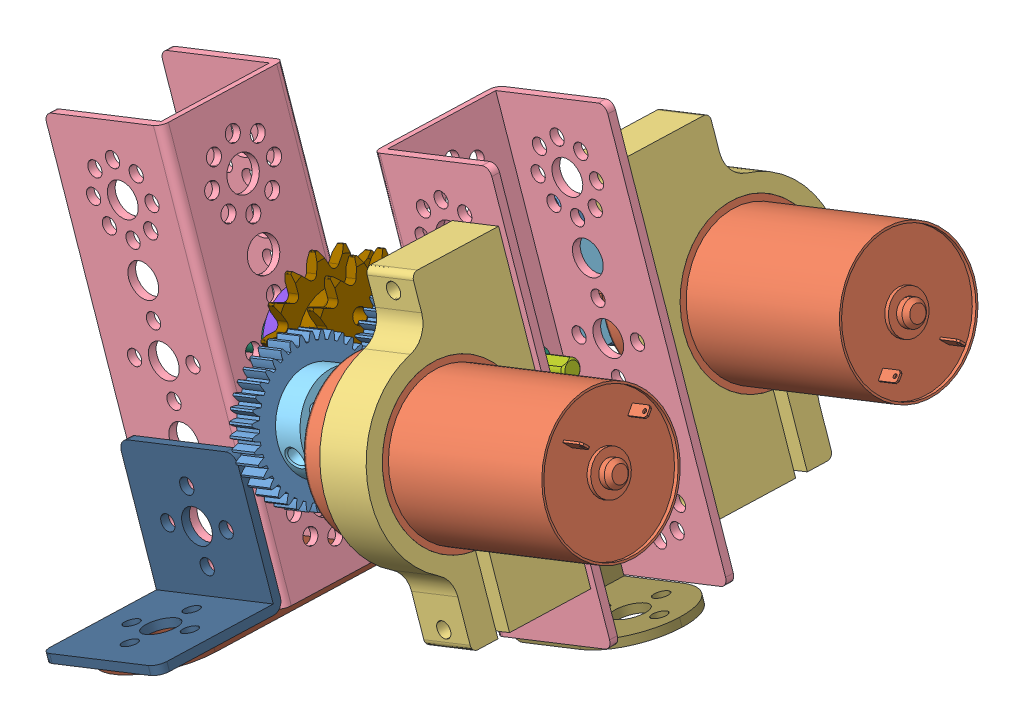
SolidWorks assembly Base Gearbox, configuration Default. Lengths in mm.
Overall size (179.16 136.45 124.21).
22 component instances, 12 part files, 56 mates.
Components (placement in the parent):
- Gear Metric 40T-5: Gear Metric 40T [PreviewCfg] at (251.3927 353.961 -2.865) x (0.93253 0.360914 -0.011317) z (-0.302942 0.799028 0.519404) size (6.2 33.53 33.53)
- Gear Metric 40T-6: Gear Metric 40T [PreviewCfg] at (251.3714 356.0218 61.1018) x (0.93253 0.360914 -0.011317) z (0.242761 -0.649832 -0.720268) size (6.2 33.53 33.53)
- DC gearhead motor-1: DC gearhead motor [Default] at (298.6742 372.0501 -9.9354) x (0.361091 -0.932043 0.030148) z (0.000333 -0.0322 -0.999481) size (37 98.8 37)
- DC gearhead motor-2: DC gearhead motor [Default] at (298.6485 374.5295 67.0247) x (-0.361091 0.932043 -0.030148) z (-0.000333 0.0322 0.999481) size (37 98.8 37)
- Tetrix Motor Mount-5: Tetrix Motor Mount [Default] at (291.2273 357.2311 -9.3463) x (-0.361091 0.932043 -0.030148) z (-0.93253 -0.360914 0.011317) size (72 44.98 12.7)
- Tetrix Motor Mount-6: Tetrix Motor Mount [Default] at (302.2979 363.9977 67.2511) x (-0.361091 0.932043 -0.030148) z (0.93253 0.360914 -0.011317) size (72 44.98 12.7)
- Tetrix 96mm-1: Tetrix 96mm [Default] at (302.6119 323.3726 30.1542) x (-0.000333 0.0322 0.999481) z (0.361091 -0.932043 0.030148) size (32 32 96)
- Hub motor shaft-5: Hub motor shaft [Default] at (257.1744 356.1987 -2.9351) x (-0.196503 0.480932 -0.854454) z (-0.93253 -0.360914 0.011317) size (22 22 9.5)
- Hub motor shaft-6: Hub motor shaft [Default] at (257.1531 358.2595 61.0317) x (0.267309 -0.668924 0.693604) z (-0.93253 -0.360914 0.011317) size (22 22 9.5)
- Tetrix 96mm-3: Tetrix 96mm [Default] at (184.0194 380.3664 28.2785) x (-0.000333 0.0322 0.999481) z (-0.361091 0.932043 -0.030148) size (32 32 96)
- Axle bronze bushing-21: Axle bronze bushing [Default] at (217.5778 341.9083 29.5287) x (0.165216 -0.398599 0.902121) z (0.93253 0.360914 -0.011317) size (11 11 12.4)
- Axle bronze bushing-22: Axle bronze bushing [Default] at (269.0535 361.8307 28.904) x (0.124395 -0.291672 0.948395) z (-0.93253 -0.360914 0.011317) size (11 11 12.4)
- Tetrix 4.7mm Axle-14: Tetrix 4.7mm Axle [Default] at (289.9422 369.9152 28.6505) x (0.124395 -0.291672 0.948395) z (-0.93253 -0.360914 0.011317) size (4.7 4.3 100)
- Gear Metric 40T-17: Gear Metric 40T [PreviewCfg] at (251.3821 354.9914 29.1184) x (0.93253 0.360914 -0.011317) z (0.105307 -0.241847 0.964583) size (6.2 33.53 33.53)
- Hub axle shaft-27: Hub axle shaft [Default] at (257.1637 357.2291 29.0483) x (0.140118 -0.332797 0.93253) z (-0.93253 -0.360914 0.011317) size (22 22 9.5)
- Tetrix 16T Sprocket-7: Tetrix 16T Sprocket [Default] at (238.5598 350.0289 29.274) x (0.140118 -0.332797 0.93253) z (-0.93253 -0.360914 0.011317) size (36 36 6.8)
- Tetrix 16T Sprocket-8: Tetrix 16T Sprocket [Default] at (231.0995 347.1415 29.3646) x (-0.140118 0.332797 -0.93253) z (0.93253 0.360914 -0.011317) size (36 36 6.8)
- Hub axle shaft-28: Hub axle shaft [Default] at (228.4884 346.131 29.3963) x (0.140118 -0.332797 0.93253) z (0.93253 0.360914 -0.011317) size (22 22 9.5)
- Tetrix Square Angle Bracket-1: Tetrix Square Angle Bracket [Default] at (212.9174 304.7726 -1.2931) x (-0.93253 -0.360914 0.011317) z (0.000333 -0.0322 -0.999481) size (32 32 32)
- Tetrix Square Angle Bracket-2: Tetrix Square Angle Bracket [Default] at (212.8961 306.8334 62.6737) x (0.93253 0.360914 -0.011317) z (-0.000333 0.0322 0.999481) size (32 32 32)
- Bracket flat-1: Bracket flat [Default] at (219.0453 289.9583 31.2028) x (0.000333 -0.0322 -0.999481) z (0.93253 0.360914 -0.011317) size (91 2 27)
- Tetrix Angle Bracket-13: Tetrix Angle Bracket [Default] at (301.2105 343.7275 30.2548) x (-0.000333 0.0322 0.999481) z (-0.93253 -0.360914 0.011317) size (27 31.5 31.5)
Mates (geometry in assembly coordinates):
- Coincident46: coincident aligned: plane of DC gearhead motor-1 through (298.6742 372.0501 -9.9354) normal (0.93253 0.360914 -0.011317); plane of Tetrix Motor Mount-5 through (298.6742 372.0501 -9.9354) normal (0.93253 0.360914 -0.011317)
- Concentric77: concentric anti-aligned: cylinder of DC gearhead motor-1 through (278.1585 364.1099 -9.6864) axis (0.93253 0.360914 -0.011317) radius 18.5; cylinder of Tetrix Motor Mount-5 through (298.6742 372.0501 -9.9354) axis (-0.93253 -0.360914 0.011317) radius 18.5
- Coincident47: coincident aligned: plane of DC gearhead motor-2 through (298.6485 374.5295 67.0247) normal (0.93253 0.360914 -0.011317); plane of Tetrix Motor Mount-6 through (298.6485 374.5295 67.0247) normal (0.93253 0.360914 -0.011317)
- Concentric78: concentric aligned: cylinder of DC gearhead motor-2 through (278.1329 366.5894 67.2737) axis (0.93253 0.360914 -0.011317) radius 18.5; cylinder of Tetrix Motor Mount-6 through (286.8054 369.9459 67.1684) axis (0.93253 0.360914 -0.011317) radius 18.5
- Parallel28: parallel anti-aligned: plane of DC gearhead motor-2 through (249.8048 354.1651 58.3617) normal (0.000333 -0.0322 -0.999481); plane of Tetrix 96mm-1 through (253.0213 407.5893 43.4327) normal (-0.000333 0.0322 0.999481)
- Parallel29: parallel anti-aligned: plane of DC gearhead motor-1 through (249.0427 354.3019 -0.0773) normal (-0.000333 0.0322 0.999481); plane of Tetrix 96mm-1 through (253.032 406.5589 11.4493) normal (0.000333 -0.0322 -0.999481)
- Concentric79: concentric anti-aligned: cylinder of DC gearhead motor-1 through (249.4344 353.2031 -2.8412) axis (0.93253 0.360914 -0.011317) radius 3; cylinder of Hub motor shaft-5 through (263.4223 358.6168 -3.011) axis (-0.93253 -0.360914 0.011317) radius 3.05
- Parallel30: parallel anti-aligned: cylinder of Tetrix 96mm-1 through (277.8246 364.7081 12.8059) axis (-0.000333 0.0322 0.999481) radius 1.85; cylinder of Hub motor shaft-5 through (260.2804 357.0452 -13.9671) axis (0.000333 -0.0322 -0.999481) radius 2.0193
- Concentric81: concentric anti-aligned: cylinder of DC gearhead motor-2 through (249.4131 355.2639 61.1256) axis (0.93253 0.360914 -0.011317) radius 3; cylinder of Hub motor shaft-6 through (263.401 360.6776 60.9559) axis (-0.93253 -0.360914 0.011317) radius 3.05
- Coincident52: coincident anti-aligned: plane of Gear Metric 40T-5 through (257.1744 356.1987 -2.9351) normal (0.93253 0.360914 -0.011317); plane of Hub motor shaft-5 through (257.1744 356.1987 -2.9351) normal (-0.93253 -0.360914 0.011317)
- Concentric83: concentric anti-aligned: cylinder of Gear Metric 40T-5 through (258.7464 352.3512 3.9005) axis (0.93253 0.360914 -0.011317) radius 1.75; cylinder of Hub motor shaft-5 through (258.7464 352.3512 3.9005) axis (-0.93253 -0.360914 0.011317) radius 1.3526
- Concentric84: concentric anti-aligned: cylinder of Gear Metric 40T-5 through (298.0193 372.0067 -3.4308) axis (-0.93253 -0.360914 0.011317) radius 4; cylinder of DC gearhead motor-1 through (249.4344 353.2031 -2.8412) axis (0.93253 0.360914 -0.011317) radius 3
- Coincident100: coincident anti-aligned: plane of Gear Metric 40T-6 through (257.1531 358.2595 61.0317) normal (0.93253 0.360914 -0.011317); plane of Hub motor shaft-6 through (257.1531 358.2595 61.0317) normal (-0.93253 -0.360914 0.011317)
- Concentric148: concentric anti-aligned: cylinder of Gear Metric 40T-6 through (255.0146 363.6109 55.4828) axis (0.93253 0.360914 -0.011317) radius 1.75; cylinder of Hub motor shaft-6 through (255.0146 363.6109 55.4828) axis (-0.93253 -0.360914 0.011317) radius 1.3526
- Concentric149: concentric anti-aligned: cylinder of Gear Metric 40T-6 through (297.998 374.0676 60.536) axis (-0.93253 -0.360914 0.011317) radius 4; cylinder of Hub motor shaft-6 through (254.542 357.2489 61.0634) axis (0.93253 0.360914 -0.011317) radius 3.95
- Parallel43: parallel aligned: plane of DC gearhead motor-2 through (249.8048 354.1651 58.3617) normal (0.000333 -0.0322 -0.999481); plane of Tetrix 96mm-1 through (253.032 406.5589 11.4493) normal (0.000333 -0.0322 -0.999481)
- Parallel44: parallel aligned: plane of DC gearhead motor-1 through (249.0427 354.3019 -0.0773) normal (-0.000333 0.0322 0.999481); plane of Tetrix 96mm-1 through (253.0213 407.5893 43.4327) normal (-0.000333 0.0322 0.999481)
- Coincident139: coincident anti-aligned: plane of Tetrix Motor Mount-6 through (299.8122 335.6678 45.7654) normal (0.000333 -0.0322 -0.999481); plane of Tetrix 96mm-1 through (253.0213 407.5893 43.4327) normal (-0.000333 0.0322 0.999481)
- Concentric205: concentric aligned: cylinder of Tetrix Motor Mount-6 through (281.1795 401.3385 43.6435) axis (-0.000333 0.0322 0.999481) radius 1.85; cylinder of Tetrix 96mm-1 through (281.1902 400.3081 11.6601) axis (-0.000333 0.0322 0.999481) radius 1.85
- Concentric206: concentric aligned: cylinder of Tetrix Motor Mount-6 through (304.2894 341.6878 45.573) axis (-0.000333 0.0322 0.999481) radius 1.85; cylinder of Tetrix 96mm-1 through (304.3 340.6574 13.5896) axis (-0.000333 0.0322 0.999481) radius 1.85
- Coincident140: coincident anti-aligned: plane of Tetrix Motor Mount-5 through (311.666 339.221 13.6383) normal (-0.000333 0.0322 0.999481); plane of Tetrix 96mm-1 through (253.032 406.5589 11.4493) normal (0.000333 -0.0322 -0.999481)
- Concentric207: concentric anti-aligned: cylinder of Tetrix Motor Mount-5 through (304.3 340.6574 13.5896) axis (0.000333 -0.0322 -0.999481) radius 1.85; cylinder of Tetrix 96mm-1 through (304.3 340.6574 13.5896) axis (-0.000333 0.0322 0.999481) radius 1.85
- Concentric208: concentric anti-aligned: cylinder of Tetrix Motor Mount-5 through (281.1902 400.3081 11.6601) axis (0.000333 -0.0322 -0.999481) radius 1.85; cylinder of Tetrix 96mm-1 through (281.1902 400.3081 11.6601) axis (-0.000333 0.0322 0.999481) radius 1.85
- Parallel59: parallel aligned: plane of Tetrix 96mm-1 through (253.032 406.5589 11.4493) normal (0.000333 -0.0322 -0.999481); plane of Tetrix 96mm-3 through (233.61 296.1497 14.9999) normal (0.000333 -0.0322 -0.999481)
- Concentric222: concentric aligned: cylinder of Tetrix 96mm-3 through (186.4313 329.8538 29.9067) axis (0.93253 0.360914 -0.011317) radius 4; cylinder of Axle bronze bushing-21 through (206.0144 337.433 29.669) axis (0.93253 0.360914 -0.011317) radius 3.925
- Coincident145: coincident anti-aligned: plane of Tetrix 96mm-3 through (233.61 296.1497 14.9999) normal (0.93253 0.360914 -0.011317); plane of Axle bronze bushing-21 through (216.2723 341.403 29.5445) normal (-0.93253 -0.360914 0.011317)
- Concentric225: concentric aligned: cylinder of Tetrix 96mm-1 through (300.2 373.8853 28.526) axis (-0.93253 -0.360914 0.011317) radius 4; cylinder of Axle bronze bushing-22 through (280.6169 366.3061 28.7636) axis (-0.93253 -0.360914 0.011317) radius 3.925
- Coincident148: coincident anti-aligned: plane of Tetrix 96mm-1 through (253.032 406.5589 11.4493) normal (-0.93253 -0.360914 0.011317); plane of Axle bronze bushing-22 through (270.359 362.336 28.8881) normal (0.93253 0.360914 -0.011317)
- Concentric226: concentric anti-aligned: cylinder of Axle bronze bushing-22 through (280.6169 366.3061 28.7636) axis (-0.93253 -0.360914 0.011317) radius 2.4; cylinder of Tetrix 4.7mm Axle-14 through (196.6891 333.8238 29.7822) axis (0.93253 0.360914 -0.011317) radius 2.35
- Distance14: distance = 10 mm aligned: plane of Tetrix 4.7mm Axle-14 through (196.6891 333.8238 29.7822) normal (-0.93253 -0.360914 0.011317); plane of Axle bronze bushing-21 through (206.0144 337.433 29.669) normal (-0.93253 -0.360914 0.011317)
- Coincident178: coincident aligned: plane of Gear Metric 40T-5 through (257.1744 356.1987 -2.9351) normal (0.93253 0.360914 -0.011317); plane of Gear Metric 40T-6 through (257.1531 358.2595 61.0317) normal (0.93253 0.360914 -0.011317)
- Distance20: distance = 10 mm anti-aligned: plane of Hub motor shaft-6 through (263.401 360.6776 60.9559) normal (0.93253 0.360914 -0.011317); plane of DC gearhead motor-2 through (272.7263 364.2868 60.8427) normal (-0.93253 -0.360914 0.011317)
- Coincident179: coincident aligned: plane of Gear Metric 40T-5 through (257.1744 356.1987 -2.9351) normal (0.93253 0.360914 -0.011317); plane of Gear Metric 40T-17 through (257.1637 357.2291 29.0483) normal (0.93253 0.360914 -0.011317)
- Concentric248: concentric anti-aligned: cylinder of Gear Metric 40T-17 through (298.0086 373.0372 28.5526) axis (-0.93253 -0.360914 0.011317) radius 4; cylinder of Hub axle shaft-27 through (254.5527 356.2185 29.08) axis (0.93253 0.360914 -0.011317) radius 3.9624
- Coincident182: coincident anti-aligned: plane of Gear Metric 40T-17 through (257.1637 357.2291 29.0483) normal (0.93253 0.360914 -0.011317); plane of Hub axle shaft-27 through (257.1637 357.2291 29.0483) normal (-0.93253 -0.360914 0.011317)
- Coincident183: coincident anti-aligned: plane of Tetrix 16T Sprocket-7 through (234.8296 348.5852 29.3193) normal (-0.93253 -0.360914 0.011317); plane of Tetrix 16T Sprocket-8 through (234.8296 348.5852 29.3193) normal (0.93253 0.360914 -0.011317)
- Concentric249: concentric anti-aligned: cylinder of Tetrix 16T Sprocket-7 through (234.8296 348.5852 29.3193) axis (0.93253 0.360914 -0.011317) radius 11; cylinder of Tetrix 16T Sprocket-8 through (234.8296 348.5852 29.3193) axis (-0.93253 -0.360914 0.011317) radius 11
- Concentric250: concentric anti-aligned: cylinder of Tetrix 16T Sprocket-7 through (238.5085 358.009 32.1297) axis (-0.93253 -0.360914 0.011317) radius 1.8; cylinder of Tetrix 16T Sprocket-8 through (225.8261 353.1006 32.2836) axis (0.93253 0.360914 -0.011317) radius 1.8
- Concentric251: concentric anti-aligned: cylinder of Tetrix 16T Sprocket-8 through (228.4884 346.131 29.3963) axis (0.93253 0.360914 -0.011317) radius 4; cylinder of Hub axle shaft-28 through (231.0995 347.1415 29.3646) axis (-0.93253 -0.360914 0.011317) radius 3.9624
- Coincident184: coincident anti-aligned: plane of Tetrix 16T Sprocket-8 through (223.0722 360.3097 35.2701) normal (-0.93253 -0.360914 0.011317); plane of Hub axle shaft-28 through (228.4884 346.131 29.3963) normal (0.93253 0.360914 -0.011317)
- Concentric252: concentric anti-aligned: cylinder of Tetrix 16T Sprocket-7 through (238.5085 358.009 32.1297) axis (-0.93253 -0.360914 0.011317) radius 1.8; cylinder of Hub axle shaft-28 through (225.8261 353.1006 32.2836) axis (0.93253 0.360914 -0.011317) radius 1.3526
- Concentric253: concentric aligned: cylinder of Tetrix 4.7mm Axle-14 through (196.6891 333.8238 29.7822) axis (0.93253 0.360914 -0.011317) radius 2.35; cylinder of Hub axle shaft-28 through (222.2405 343.7129 29.4721) axis (0.93253 0.360914 -0.011317) radius 2.3495
- Distance22: distance = 5 mm anti-aligned: plane of Axle bronze bushing-21 through (217.5778 341.9083 29.5287) normal (0.93253 0.360914 -0.011317); plane of Hub axle shaft-28 through (222.2405 343.7129 29.4721) normal (-0.93253 -0.360914 0.011317)
- Distance25: distance = 58 mm anti-aligned: plane of Tetrix 96mm-1 through (253.032 406.5589 11.4493) normal (-0.93253 -0.360914 0.011317); plane of Tetrix 96mm-3 through (233.61 296.1497 14.9999) normal (0.93253 0.360914 -0.011317)
- Coincident190: coincident anti-aligned: plane of Tetrix 96mm-3 through (233.5993 297.1802 46.9833) normal (-0.000333 0.0322 0.999481); plane of Tetrix Square Angle Bracket-2 through (222.0444 327.0055 46.0186) normal (0.000333 -0.0322 -0.999481)
- Concentric254: concentric anti-aligned: cylinder of Tetrix 96mm-3 through (212.912 305.2878 14.6986) axis (-0.000333 0.0322 0.999481) radius 4; cylinder of Tetrix Square Angle Bracket-2 through (212.8907 307.3486 78.6654) axis (0.000333 -0.0322 -0.999481) radius 4
- Concentric255: concentric anti-aligned: cylinder of Tetrix 96mm-3 through (215.8008 297.8315 14.9398) axis (-0.000333 0.0322 0.999481) radius 1.85; cylinder of Tetrix Square Angle Bracket-2 through (215.7795 299.8923 78.9066) axis (0.000333 -0.0322 -0.999481) radius 1.85
- Coincident191: coincident anti-aligned: plane of Tetrix 96mm-3 through (233.61 296.1497 14.9999) normal (0.000333 -0.0322 -0.999481); plane of Tetrix Square Angle Bracket-1 through (192.2141 314.4259 14.3973) normal (-0.000333 0.0322 0.999481)
- Concentric256: concentric aligned: cylinder of Tetrix 96mm-3 through (212.912 305.2878 14.6986) axis (-0.000333 0.0322 0.999481) radius 4; cylinder of Tetrix Square Angle Bracket-1 through (212.9227 304.2574 -17.2848) axis (-0.000333 0.0322 0.999481) radius 4
- Concentric257: concentric aligned: cylinder of Tetrix 96mm-3 through (210.0233 312.7441 14.4574) axis (-0.000333 0.0322 0.999481) radius 1.85; cylinder of Tetrix Square Angle Bracket-1 through (210.034 311.7137 -17.526) axis (-0.000333 0.0322 0.999481) radius 1.85
- Coincident192: coincident anti-aligned: plane of Tetrix Square Angle Bracket-1 through (203.7797 283.5701 -16.6213) normal (0.361091 -0.932043 0.030148); plane of Bracket flat-1 through (206.0799 287.4831 76.8019) normal (-0.361091 0.932043 -0.030148)
- Concentric258: concentric anti-aligned: cylinder of Tetrix Square Angle Bracket-1 through (207.1399 319.6853 -1.7754) axis (0.361091 -0.932043 0.030148) radius 4; cylinder of Bracket flat-1 through (219.417 287.9958 -0.7504) axis (-0.361091 0.932043 -0.030148) radius 4
- Concentric259: concentric anti-aligned: cylinder of Tetrix Square Angle Bracket-2 through (207.1186 321.7461 62.1914) axis (0.361091 -0.932043 0.030148) radius 4; cylinder of Bracket flat-1 through (219.3957 290.0566 63.2164) axis (-0.361091 0.932043 -0.030148) radius 4
- Concentric260: concentric aligned: cylinder of Tetrix 96mm-1 through (311.7549 344.0599 29.4907) axis (-0.93253 -0.360914 0.011317) radius 4; cylinder of Tetrix Angle Bracket-13 through (313.1537 344.6013 29.4738) axis (-0.93253 -0.360914 0.011317) radius 4
- Concentric261: concentric aligned: cylinder of Tetrix 96mm-1 through (308.8662 351.5163 29.2495) axis (-0.93253 -0.360914 0.011317) radius 1.85; cylinder of Tetrix Angle Bracket-13 through (310.265 352.0576 29.2326) axis (-0.93253 -0.360914 0.011317) radius 1.85
- Coincident194: coincident anti-aligned: plane of Tetrix 96mm-1 through (254.8964 407.3451 13.4257) normal (0.93253 0.360914 -0.011317); plane of Tetrix Angle Bracket-13 through (278.9088 345.3804 15.9302) normal (-0.93253 -0.360914 0.011317)
